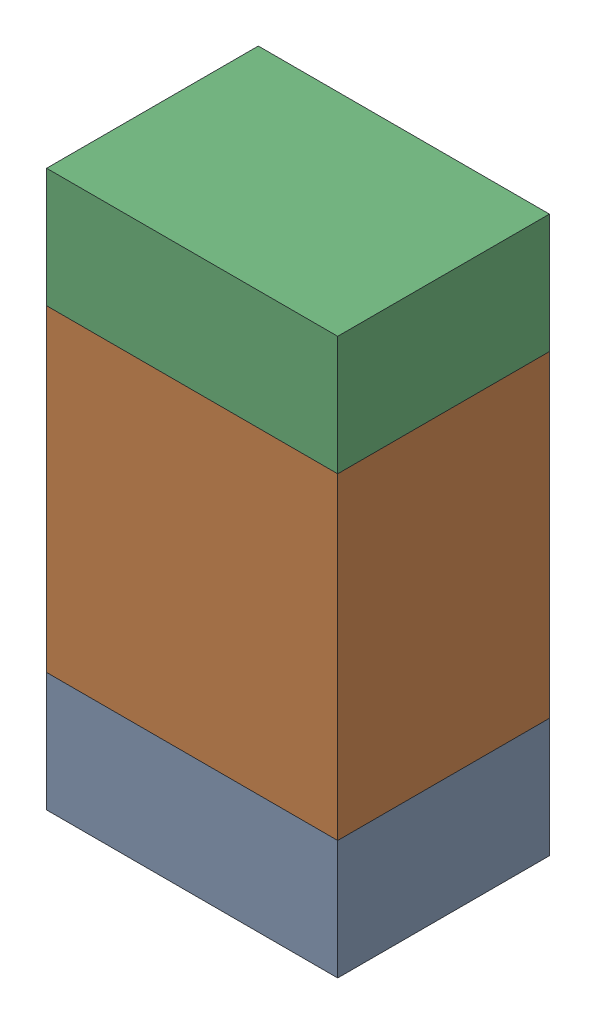
SolidWorks assembly R101_2PCB, configuration Default. Lengths in mm.
Overall size (0.55 1.05 0.4).
6 component instances, 2 part files, 0 mates.
Components (placement in the parent):
- 846483288-1: 846483288 [Default] at (117.0999 96.8876 0) size (0.55 0.22 0.4)
  - Extruded_12-1: Extruded_12 [Default] at origin size (0.55 0.22 0.4)
- 846483424-1: 846483424 [Default] at (117.0999 97.3001 0) size (0.55 0.6 0.4)
  - Extruded_13-1: Extruded_13 [Default] at origin size (0.55 0.6 0.4)
- 846483288-2: 846483288 [Default] at (117.0999 97.7126 0) size (0.55 0.22 0.4)
  - Extruded_12-1: Extruded_12 [Default] at origin size (0.55 0.22 0.4)
